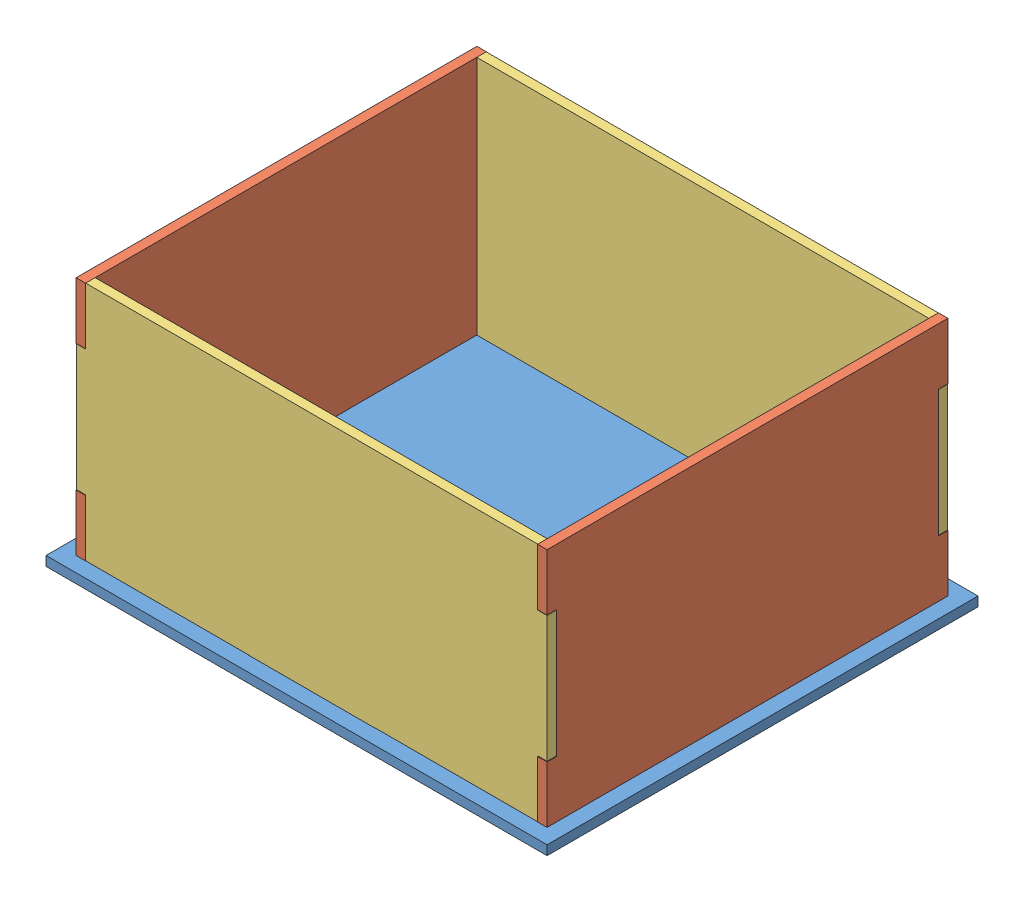
SolidWorks assembly MOLD, Box, FRONT, configuration Default. Lengths in mm.
Overall size (158.75 79.2 136.53).
5 component instances, 3 part files, 12 mates.
Components (placement in the parent):
- MOLD, Box, Front, Bottom-1: MOLD, Box, Front, Bottom [Default] at (-99.4767 5.4191 48.8108) size (158.75 3 136.53)
- MOLD, Box, Front, Side1-1: MOLD, Box, Front, Side1 [Default] at (-26.3628 45.0177 48.8108) x (0 0 1) z (-1 0 0) size (127 79.15 3)
- MOLD, Box, Front, Side1-2: MOLD, Box, Front, Side1 [Default] at (-172.5906 45.0177 48.8108) x (0 0 1) z (-1 0 0) size (127 79.15 3)
- MOLD, Box, Front, Side2-1: MOLD, Box, Front, Side2 [Default] at (-99.4767 45.0177 110.7614) size (149.12 79.15 3)
- MOLD, Box, Front, Side2-2: MOLD, Box, Front, Side2 [Default] at (-99.4767 45.0177 -13.1398) size (149.12 79.15 3)
Mates (geometry in assembly coordinates):
- Coincident1: coincident anti-aligned: plane of MOLD, Box, Front, Bottom-1 through (-20.1017 6.9177 -19.4517) normal (0 1 0); plane of MOLD, Box, Front, Side1-1 through (-27.8614 6.9177 -14.6892) normal (0 -1 0)
- Coincident2: coincident anti-aligned: plane of MOLD, Box, Front, Bottom-1 through (-20.1017 6.9177 -19.4517) normal (0 1 0); plane of MOLD, Box, Front, Side1-2 through (-174.0892 6.9177 -14.6892) normal (0 -1 0)
- Coincident3: coincident aligned: plane of MOLD, Box, Front, Side1-1 through (-24.8642 65.1447 109.2628) normal (0 0 1); plane of MOLD, Box, Front, Side1-2 through (-171.092 65.1447 109.2628) normal (0 0 1)
- Width4: width anti-aligned: plane of MOLD, Box, Front, Side1-1 through (-27.8614 83.1177 112.3108) normal (-1 0 0); plane of MOLD, Box, Front, Side1-1 through (-24.8642 83.1177 112.3108) normal (1 0 0); plane of MOLD, Box, Front, Bottom-1 through (-27.8868 3.9205 28.7854) normal (1 0 0); plane of MOLD, Box, Front, Bottom-1 through (-24.8388 3.9205 28.7854) normal (-1 0 0)
- Width5: width anti-aligned: plane of MOLD, Box, Front, Bottom-1 through (-24.8388 3.9205 28.7854) normal (0 0 1); plane of MOLD, Box, Front, Bottom-1 through (-24.8388 3.9205 68.8362) normal (0 0 -1); plane of MOLD, Box, Front, Side1-1 through (-24.8642 6.9177 28.8108) normal (0 0 -1); plane of MOLD, Box, Front, Side1-1 through (-24.8642 6.9177 68.8108) normal (0 0 1)
- Width6: width aligned: plane of MOLD, Box, Front, Side1-2 through (-174.0892 83.1177 112.3108) normal (-1 0 0); plane of MOLD, Box, Front, Side1-2 through (-171.092 83.1177 112.3108) normal (1 0 0); plane of MOLD, Box, Front, Bottom-1 through (-171.0666 3.9205 28.7854) normal (-1 0 0); plane of MOLD, Box, Front, Bottom-1 through (-174.1146 3.9205 28.7854) normal (1 0 0)
- Coincident4: coincident anti-aligned: plane of MOLD, Box, Front, Side1-2 through (-171.092 65.1447 109.2628) normal (0 0 1); plane of MOLD, Box, Front, Side2-1 through (-27.8614 83.1177 109.2628) normal (0 0 -1)
- Coincident5: coincident anti-aligned: plane of MOLD, Box, Front, Bottom-1 through (-20.1017 6.9177 -19.4517) normal (0 1 0); plane of MOLD, Box, Front, Side2-1 through (-171.092 6.9177 112.26) normal (0 -1 0)
- Width7: width anti-aligned: plane of MOLD, Box, Front, Side2-1 through (-171.092 6.9177 112.26) normal (-1 0 0); plane of MOLD, Box, Front, Side2-1 through (-27.8614 6.9177 112.26) normal (1 0 0); plane of MOLD, Box, Front, Side1-2 through (-171.092 83.1177 112.3108) normal (1 0 0); plane of MOLD, Box, Front, Side1-1 through (-27.8614 83.1177 112.3108) normal (-1 0 0)
- Coincident6: coincident anti-aligned: plane of MOLD, Box, Front, Side1-1 through (-24.8642 65.1447 -11.6412) normal (0 0 -1); plane of MOLD, Box, Front, Side2-2 through (-27.8614 83.1177 -11.6412) normal (0 0 1)
- Coincident7: coincident aligned: plane of MOLD, Box, Front, Side2-1 through (-24.915 25.0177 109.2628) normal (1 0 0); plane of MOLD, Box, Front, Side2-2 through (-24.915 25.0177 -14.6384) normal (1 0 0)
- Coincident8: coincident anti-aligned: plane of MOLD, Box, Front, Bottom-1 through (-20.1017 6.9177 -19.4517) normal (0 1 0); plane of MOLD, Box, Front, Side2-2 through (-171.092 6.9177 -11.6412) normal (0 -1 0)
